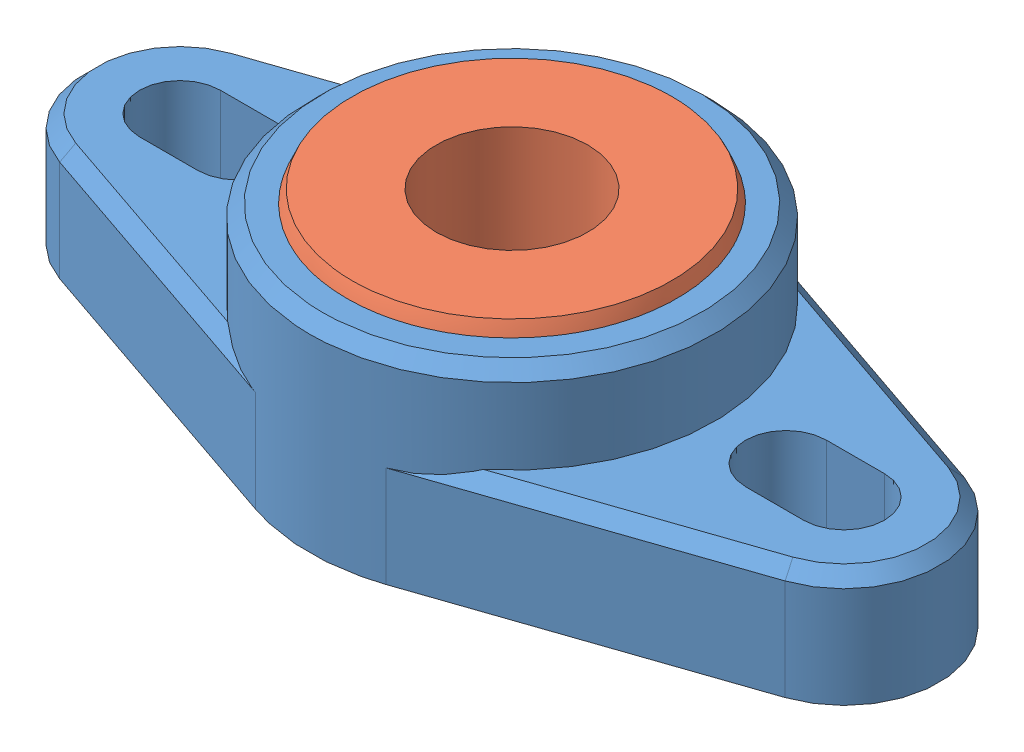
SolidWorks assembly Self-Aligning Bearings 6, configuration Default. Lengths in mm.
Overall size (33.8 8.5 16).
3 component instances, 2 part files, 0 mates.
Components (placement in the parent):
- Self-Aligning Bearings 6.STEP-1: Self-Aligning Bearings 6.STEP [Default] at origin size (33.8 8.5 16)
  - ohisje_6.STEP-1: ohisje_6.STEP [Default] at origin size (33.8 8 16)
  - Krogla_6.STEP-1: Krogla_6.STEP [Default] at (0 1.25 0) size (14 6 14)
